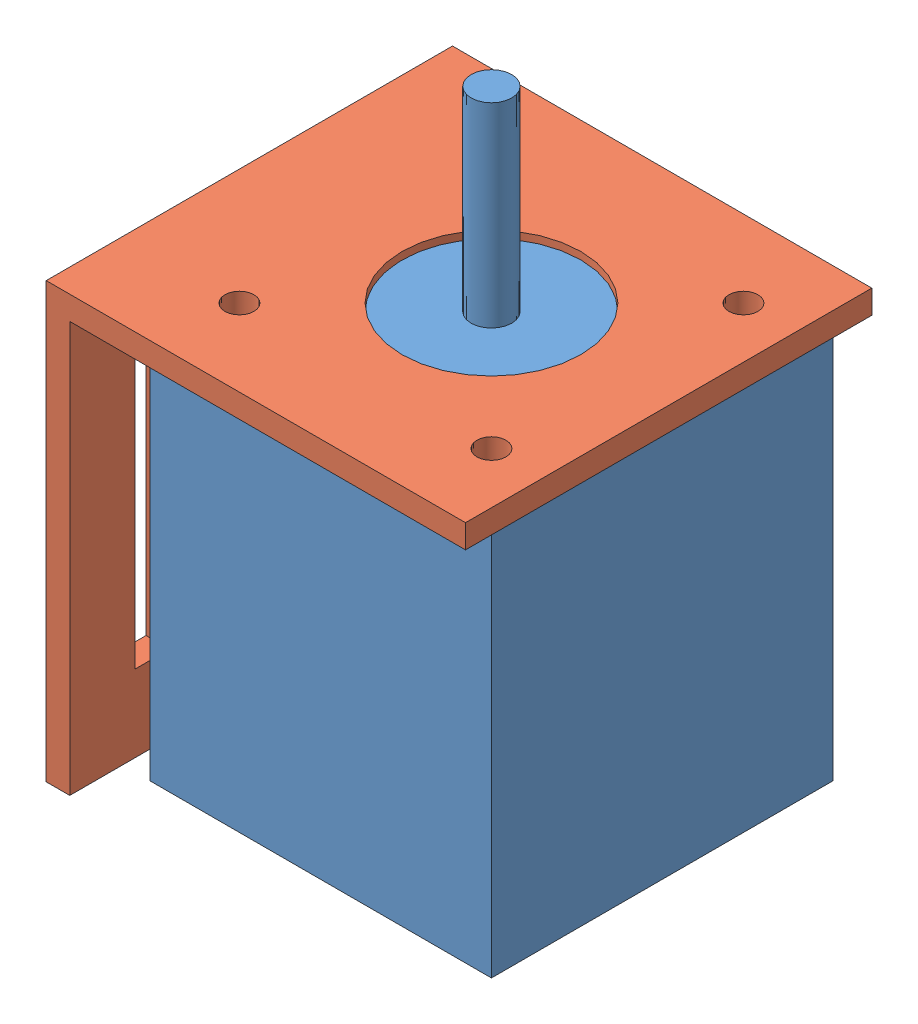
SolidWorks assembly motorMountedAssem, configuration Default. Lengths in mm.
Overall size (51.58 76.5 49.98).
2 component instances, 2 part files, 5 mates.
Components (placement in the parent):
- motor-1: motor [Default] at (1.9535 7.9798 75.9423) size (42 74 42)
- motorMount-2: motorMount [Default] at (44.7535 58.8798 79.9323) x (-1 0 0) z (0 0 1) size (51.58 53.4 49.98)
Mates (geometry in assembly coordinates):
- Concentric1: concentric aligned: circle of motor-1; circle of ?
- Coincident1: coincident anti-aligned: plane of motor-1 through (1.9535 55.9798 75.9423) normal (0 1 0); plane of ? through (27.5356 55.9798 87.7866) normal (0 -1 0)
- Concentric3: concentric anti-aligned: cylinder of motor-1 through (22.9535 57.9798 54.9423) axis (0 -1 0) radius 11; cylinder of motorMount-2 through (22.9535 5.4798 54.9423) axis (0 1 0) radius 11
- Concentric4: concentric aligned: circle of motor-1; circle of motorMount-2
- Coincident2: coincident anti-aligned: plane of motor-1 through (1.9535 55.9798 75.9423) normal (0 1 0); plane of motorMount-2 through (44.7535 55.9798 79.9323) normal (0 -1 0)
